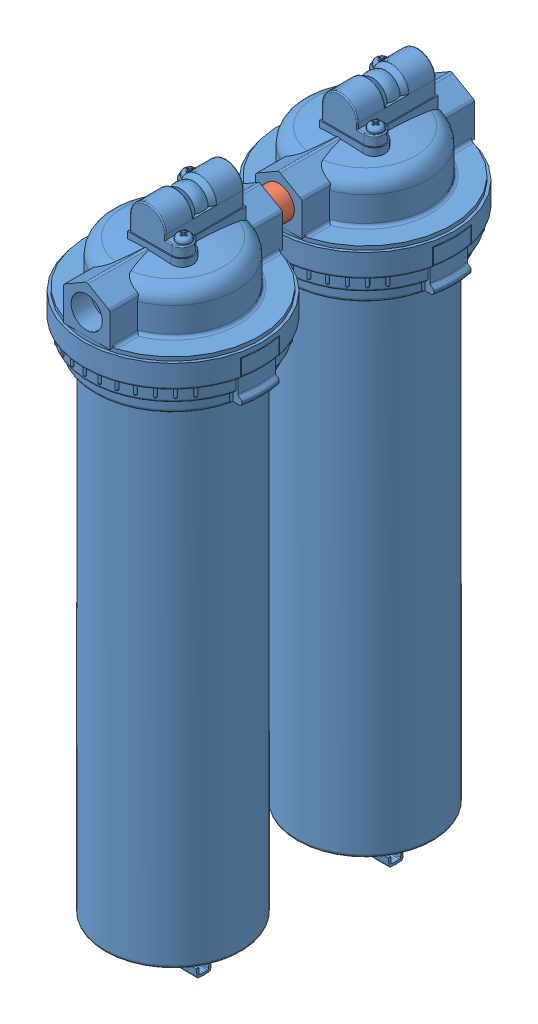
SolidWorks assembly ReadingTech_4P-090-M04-DCPi, configuration Default. Lengths in mm.
Overall size (121.86 454.52 252.73).
3 component instances, 2 part files, 3 mates.
Components (placement in the parent):
- ReadingTech_3P-090-M04-Pi-1: ReadingTech_3P-090-M04-Pi [Default] at (-38.4832 -190.5864 13.2877) size (121.86 454.52 121.67)
- ReadingTech_3P-090-M04-Pi-2: ReadingTech_3P-090-M04-Pi [Default] at (-38.4832 -190.5864 -117.7763) size (121.86 454.52 121.67)
- ReadingTech- 90,150cfm_connector_.5in-1: ReadingTech- 90,150cfm_connector_.5in [Default] at (-38.4832 194.3506 -45.6403) x (1 0 0) z (0 1 0) size (21.34 13.21 21.34)
Mates (geometry in assembly coordinates):
- Coincident1: coincident anti-aligned: circle of ReadingTech_3P-090-M04-Pi-2; circle of ReadingTech- 90,150cfm_connector_.5in-1
- Coincident2: coincident aligned: circle of ReadingTech_3P-090-M04-Pi-1; circle of ReadingTech- 90,150cfm_connector_.5in-1
- Coincident3: coincident aligned: plane of ReadingTech_3P-090-M04-Pi-1 through (-22.6717 203.1136 72.2157) normal (1 0 0); plane of ReadingTech_3P-090-M04-Pi-2 through (-22.6717 203.1136 -58.8483) normal (1 0 0)
